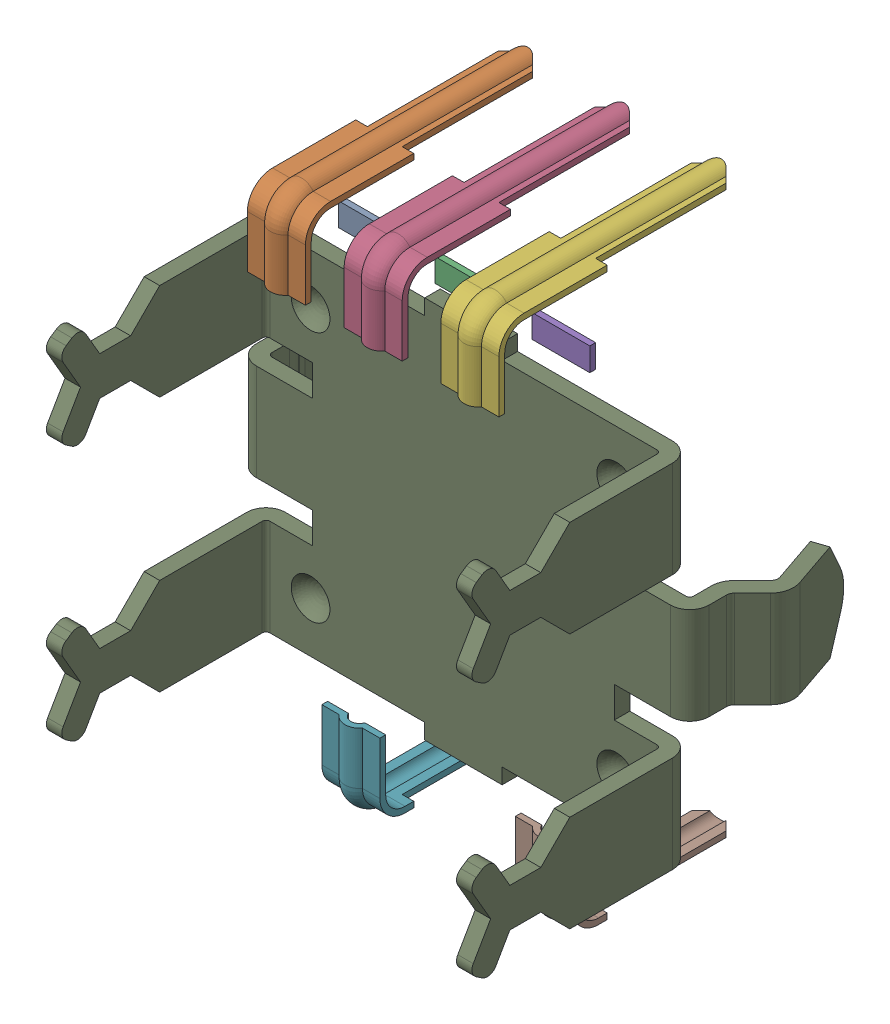
SolidWorks assembly Imported, configuration Défaut. Lengths in mm.
Overall size (13.1 14.95 9.45).
12 component instances, 4 part files, 0 mates.
Components (placement in the parent):
- Imported_2-1: Imported_2 [Défaut] at (-2.5 7.575 -10.2243) x (0 -1 0) z (0 0 1) size (2.34 1.5 6.65)
  - SOLID-1: SOLID [Défaut] at origin size (0.6 1.5 0.15)
  - SOLID_2-1: SOLID_2 [Défaut] at origin size (2.15 1.5 6.65)
- Imported_2-2: Imported_2 [Défaut] at (0 7.575 -10.2243) x (0 -1 0) z (0 0 1) size (2.34 1.5 6.65)
  - SOLID-1: SOLID [Défaut] at origin size (0.6 1.5 0.15)
  - SOLID_2-1: SOLID_2 [Défaut] at origin size (2.15 1.5 6.65)
- Imported_2-3: Imported_2 [Défaut] at (2.5 7.575 -10.2243) x (0 -1 0) z (0 0 1) size (2.34 1.5 6.65)
  - SOLID-1: SOLID [Défaut] at origin size (0.6 1.5 0.15)
  - SOLID_2-1: SOLID_2 [Défaut] at origin size (2.15 1.5 6.65)
- Imported_4-1: Imported_4 [Défaut] at (-2.5 -7.075 -10.2243) x (0 1 0) z (0 0 1) size (2.15 1.5 4.73)
- Imported_4-2: Imported_4 [Défaut] at (2.5 -7.075 -10.2243) x (0 1 0) z (0 0 1) size (2.15 1.5 4.73)
- Imported_5-1: Imported_5 [Défaut] at (-24.7094 3.8245 8.4125) size (13.1 9.9 9.18)
